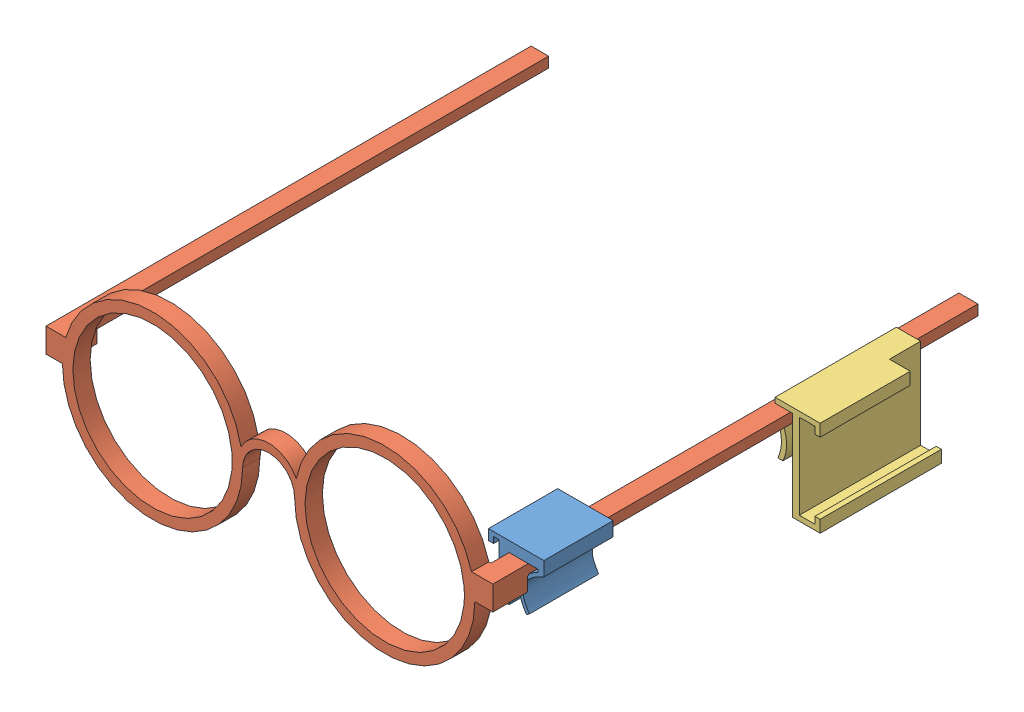
SolidWorks assembly Glasses-with-clips-for-poster, configuration Standard. Lengths in mm.
Overall size (137.47 52 140).
3 component instances, 3 part files, 4 mates.
Components (placement in the parent):
- Clip-4-1: Clip-4 [Standard] at (-13.1637 -12.7473 41.4793) size (16 16 20)
- Brille-1: Brille [Standard] at (-70.8542 -14.7473 66.7132) size (128.94 52 140)
- Clip-RFDuino-Board-7-1: Clip-RFDuino-Board-7 [Standard] at (-4.6279 -19.9973 -14.2092) x (-1 0 0) z (0 0 -1) size (13 27.5 35)
Mates (geometry in assembly coordinates):
- Deckungsgleich3: coincident anti-aligned: plane of Clip-4-1 through (-11.6637 -12.7473 61.4793) normal (1 0 0); plane of Brille-1 through (-11.6637 -7.7473 71.7132) normal (-1 0 0)
- Deckungsgleich4: coincident anti-aligned: plane of Clip-4-1 through (-13.1637 -7.7473 61.4793) normal (0 -1 0); plane of Brille-1 through (-70.8542 -7.7473 66.7132) normal (0 1 0)
- Deckungsgleich5: coincident anti-aligned: plane of Brille-1 through (-70.8542 -7.7473 66.7132) normal (0 1 0); plane of Clip-RFDuino-Board-7-1 through (-4.6279 -7.7473 -49.2092) normal (0 -1 0)
- Parallel1: parallel anti-aligned: plane of Clip-4-1 through (-13.1637 -12.7473 41.4793) normal (0 0 -1); plane of Clip-RFDuino-Board-7-1 through (-4.6279 -19.9973 -14.2092) normal (0 0 1)
